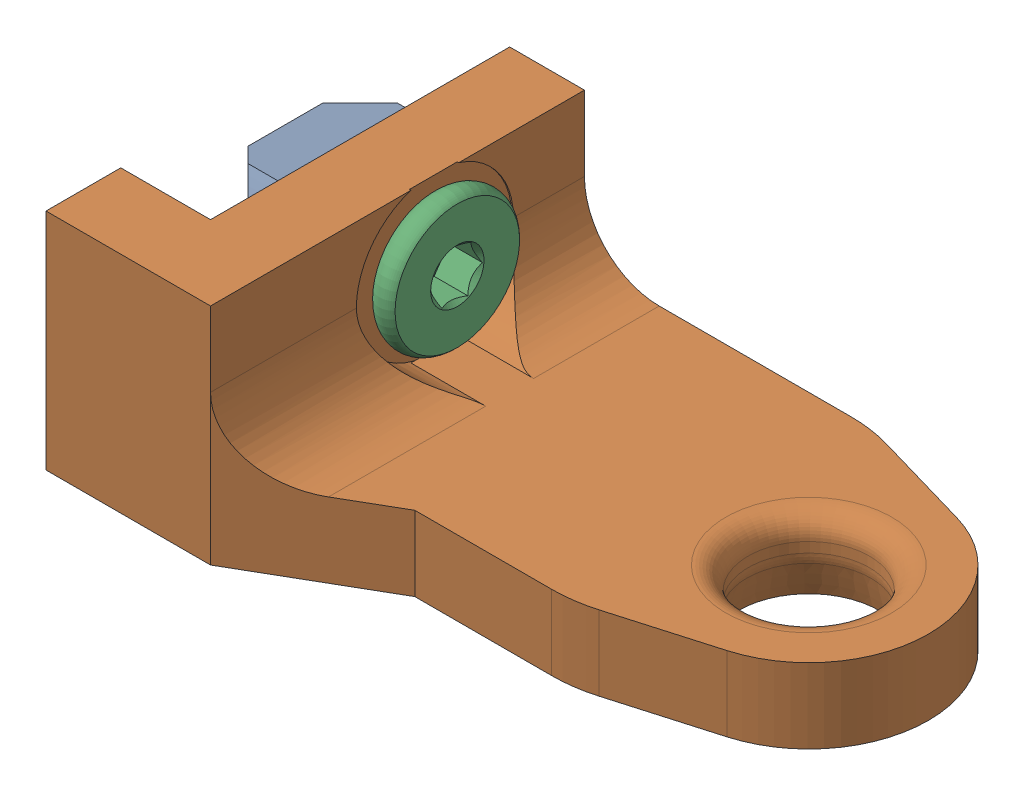
SolidWorks assembly front_left_leadscrew_retainer_assembly, configuration Default. Lengths in mm.
Overall size (44 16.25 25).
3 component instances, 3 part files, 0 mates.
Components (placement in the parent):
- m5_locking_t_nut_20x20_generic-1: m5_locking_t_nut_20x20_generic [Default] at (-34.929 325.386 466.8395) x (0 0 1) z (0 1 0) size (10 4.5 6)
- compact_front_leadscrew_retainer_Front Left Leadscrew Retainer-1: compact_front_leadscrew_retainer_Front Left Leadscrew Retainer [Default] at (0.071 318.386 466.8395) x (0 0 -1) z (1 0 0) size (25 15 44)
- m5_low_profile_screw_template_M5 x 10-1: m5_low_profile_screw_template_M5 x 10 [Default] at (-34.929 328.386 466.8395) x (-1 0 0) z (0 0.562768 0.826615) size (11.62 9 9)
